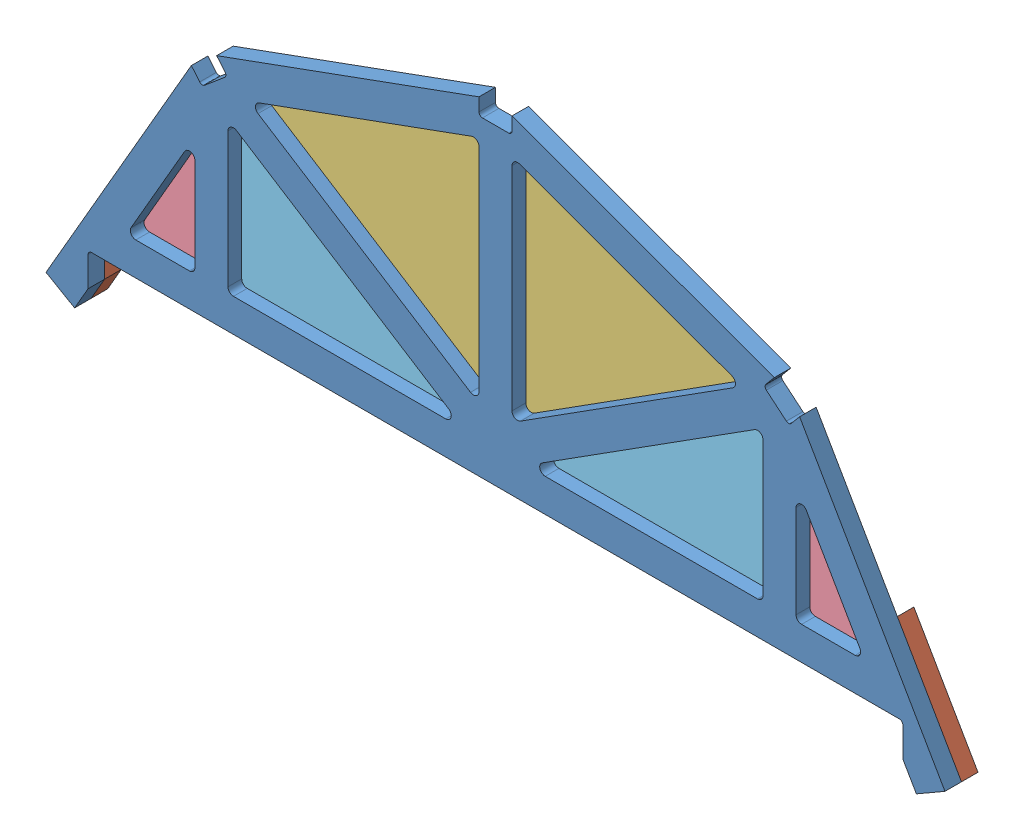
SolidWorks assembly truss3-outside, configuration Default. Lengths in mm.
Overall size (1036.94 444.07 38.1).
9 component instances, 5 part files, 12 mates.
Components (placement in the parent):
- truss3-1: truss3 [outsides] at origin size (1036.94 444.07 19.05)
- truss3-supports-2: truss3-supports [Default] at origin size (73.97 147.17 19.05)
- truss3-supports-6: truss3-supports [Default] at (0 0 -38.1) x (-1 0 0) z (0 0 -1) size (73.97 147.17 19.05)
- truss3-plexi-Center-1: truss3-plexi-Center [Default] at origin size (264.15 264.08 3.18)
- truss3-plexi-End-1: truss3-plexi-End [Default] at origin size (80.92 126.21 3.18)
- truss3-plexi-Middle-1: truss3-plexi-Middle [Default] at origin size (263.96 174.76 3.18)
- truss3-plexi-End-2: truss3-plexi-End [Default] at (0 0 -15.875) x (-1 0 0) z (0 0 -1) size (80.92 126.21 3.18)
- truss3-plexi-Middle-2: truss3-plexi-Middle [Default] at (0 0 -15.875) x (-1 0 0) z (0 0 -1) size (263.96 174.76 3.18)
- truss3-plexi-Center-2: truss3-plexi-Center [Default] at (0 0 -15.875) x (-1 0 0) z (0 0 -1) size (264.15 264.08 3.18)
Mates (geometry in assembly coordinates):
- Coincident3: coincident aligned: plane of truss3-1 through (340.6702 439.7326 9.525) normal (0.866025 0.5 0); plane of truss3-supports-2 through (518.4702 131.774 -28.575) normal (0.866025 0.5 0)
- Coincident4: coincident aligned: plane of truss3-1 through (485.4746 112.724 9.525) normal (0.5 -0.866025 0); plane of truss3-supports-2 through (485.4746 112.724 -28.575) normal (0.5 -0.866025 0)
- Coincident5: coincident anti-aligned: plane of truss3-1 through (0 0 -9.525) normal (0 0 -1); plane of truss3-supports-2 through (465.9313 173.8312 -9.525) normal (0 0 1)
- Concentric1: concentric aligned: circle of truss3-1; circle of truss3-plexi-Middle-1
- Concentric2: concentric aligned: circle of truss3-1; circle of truss3-plexi-Middle-1
- Coincident7: coincident anti-aligned: plane of truss3-1 through (302.2392 377.9556 -6.35) normal (0 0 -1); plane of truss3-plexi-Middle-1 through (302.2392 377.9556 -6.35) normal (0 0 1)
- Concentric3: concentric aligned: circle of truss3-1; circle of truss3-plexi-End-1
- Concentric4: concentric aligned: circle of truss3-1; circle of truss3-plexi-End-1
- Coincident8: coincident anti-aligned: plane of truss3-1 through (353.0392 222.25 -6.35) normal (0 0 -1); plane of truss3-plexi-End-1 through (353.0392 329.4088 -6.35) normal (0 0 1)
- Concentric5: concentric aligned: circle of truss3-1; circle of truss3-plexi-Center-1
- Concentric6: concentric aligned: circle of truss3-1; circle of truss3-plexi-Center-1
- Coincident9: coincident anti-aligned: plane of truss3-1 through (270.4954 417.9714 -6.35) normal (0 0 -1); plane of truss3-plexi-Center-1 through (25.4 262.1473 -6.35) normal (0 0 1)
